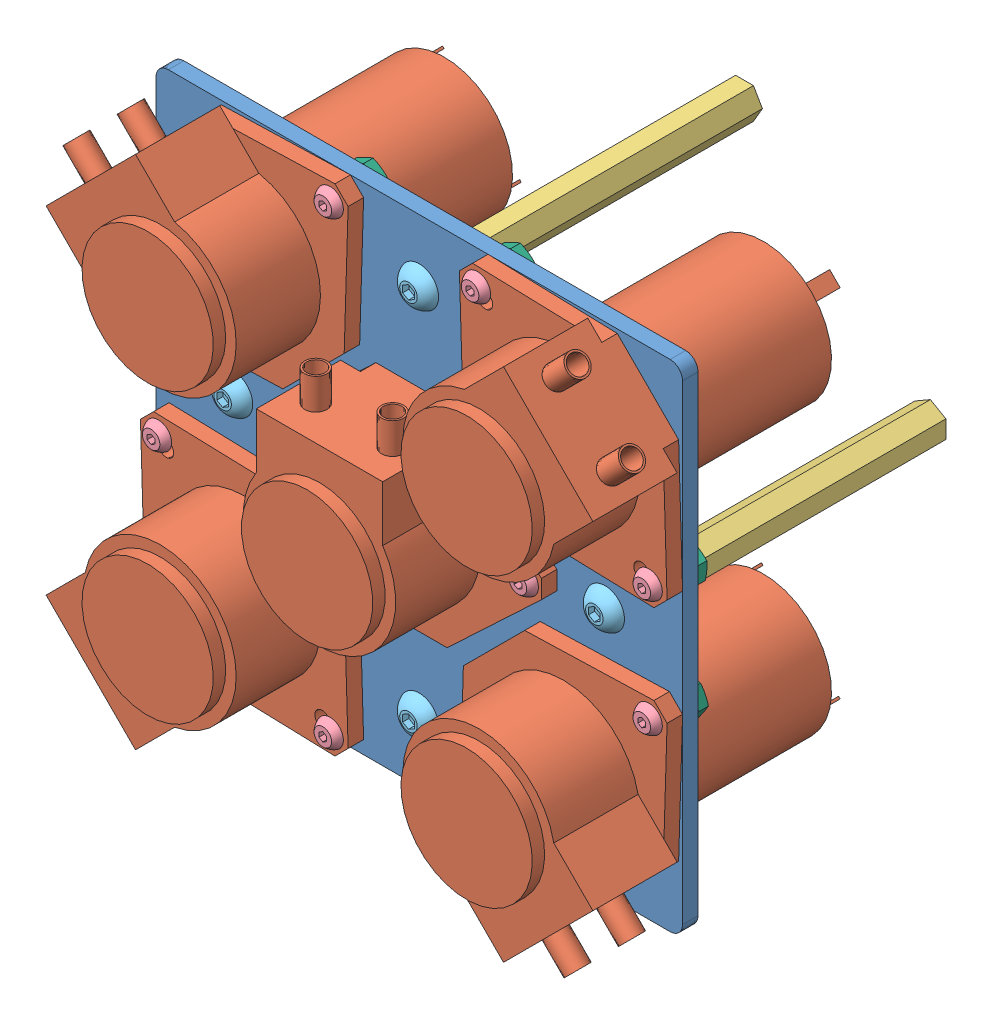
SolidWorks assembly pump_assembly, configuration Default. Lengths in mm.
Overall size (142.61 136.26 89.66).
34 component instances, 6 part files, 117 mates.
Components (placement in the parent):
- pump_mount02-1: pump_mount02 [Default] at (61.8269 35.897 80.89) size (107.95 101.6 3.17)
- water_pump-1: water_pump [Default] at (9.0816 76.7777 87.24) x (-0.707107 0.707107 0) z (-0.707107 -0.707107 0) size (56.39 67.44 46.48)
- water_pump-2: water_pump [Default] at (70.5317 64.9284 87.24) x (-0.707107 -0.707107 0) z (0.707107 -0.707107 0) size (56.39 67.44 46.48)
- water_pump-6: water_pump [Default] at (20.9309 131.8777 87.24) x (0.707107 0.707107 0) z (-0.707107 0.707107 0) size (56.39 67.44 46.48)
- water_pump-8: water_pump [Default] at (54.11 95.6216 87.24) x (1 0 0) z (0 1 0) size (56.39 67.44 46.48)
- 8-32x2p5_standoff_f-f-PFC-HRD-0008-2: 8-32x2p5_standoff_f-f-PFC-HRD-0008 [Default] at (90.9051 102.1286 17.39) x (0.238502 0.971142 0) z (0.971142 -0.238502 0) size (7.12 63.5 7.04)
- water_pump-7: water_pump [Default] at (82.381 120.0284 87.24) x (0.707107 -0.707107 0) z (0.707107 0.707107 0) size (56.39 67.44 46.48)
- 8-32x2p5_standoff_f-f-PFC-HRD-0008-3: 8-32x2p5_standoff_f-f-PFC-HRD-0008 [Default] at (49.9946 67.0664 17.39) x (-0.279022 0.960285 0) z (0.960285 0.279022 0) size (7.12 63.5 7.04)
- 8-32x2p5_standoff_f-f-PFC-HRD-0008-4: 8-32x2p5_standoff_f-f-PFC-HRD-0008 [Default] at (7.9417 106.3919 17.39) x (-0.721782 0.69212 0) z (0.69212 0.721782 0) size (7.12 63.5 7.04)
- 8-32x2p5_standoff_f-f-PFC-HRD-0008-5: 8-32x2p5_standoff_f-f-PFC-HRD-0008 [Default] at (42.0057 129.4293 80.89) x (-0.971142 -0.238502 0) z (0.238502 -0.971142 0) size (7.12 63.5 7.04)
- S-004-038-BTN-H-SS-001-440x3_8-button-head-screw-1: S-004-038-BTN-H-SS-001-440x3_8-button-head-screw [Default] at (96.0244 110.3185 87.24) x (1 0 0) z (0 -1 0) size (5.41 11.02 5.41)
- S-004-038-BTN-H-SS-001-440x3_8-button-head-screw-2: S-004-038-BTN-H-SS-001-440x3_8-button-head-screw [Default] at (30.6408 145.5211 87.24) x (1 0 0) z (0 -1 0) size (5.41 11.02 5.41)
- S-004-038-BTN-H-SS-001-440x3_8-button-head-screw-3: S-004-038-BTN-H-SS-001-440x3_8-button-head-screw [Default] at (60.8218 145.5211 87.24) x (1 0 0) z (0 -1 0) size (5.41 11.02 5.41)
- S-004-038-BTN-H-SS-001-440x3_8-button-head-screw-4: S-004-038-BTN-H-SS-001-440x3_8-button-head-screw [Default] at (-4.5618 110.3185 87.24) x (1 0 0) z (0 -1 0) size (5.41 11.02 5.41)
- S-004-038-BTN-H-SS-001-440x3_8-button-head-screw-9: S-004-038-BTN-H-SS-001-440x3_8-button-head-screw [Default] at (96.0244 86.4876 87.24) x (1 0 0) z (0 -1 0) size (5.41 11.02 5.41)
- S-004-038-BTN-H-SS-001-440x3_8-button-head-screw-10: S-004-038-BTN-H-SS-001-440x3_8-button-head-screw [Default] at (60.8218 51.2849 87.24) x (1 0 0) z (0 -1 0) size (5.41 11.02 5.41)
- S-004-038-BTN-H-SS-001-440x3_8-button-head-screw-11: S-004-038-BTN-H-SS-001-440x3_8-button-head-screw [Default] at (30.6408 51.2849 87.24) x (1 0 0) z (0 -1 0) size (5.41 11.02 5.41)
- S-004-038-BTN-H-SS-001-440x3_8-button-head-screw-12: S-004-038-BTN-H-SS-001-440x3_8-button-head-screw [Default] at (70.6233 98.403 87.24) x (1 0 0) z (0 -1 0) size (5.41 11.02 5.41)
- S-004-038-BTN-H-SS-001-440x3_8-button-head-screw-13: S-004-038-BTN-H-SS-001-440x3_8-button-head-screw [Default] at (20.8393 98.403 87.24) x (1 0 0) z (0 -1 0) size (5.41 11.02 5.41)
- S-004-038-BTN-H-SS-001-440x3_8-button-head-screw-14: S-004-038-BTN-H-SS-001-440x3_8-button-head-screw [Default] at (-4.5618 86.4876 87.24) x (1 0 0) z (0 -1 0) size (5.41 11.02 5.41)
- S-008-038-BTN-H-SS-001-832x3_8-button-head-screw-2: S-008-038-BTN-H-SS-001-832x3_8-button-head-screw [Default] at (45.7313 136.503 84.065) x (1 0 0) z (0 -1 0) size (7.92 11.73 7.92)
- S-008-038-BTN-H-SS-001-832x3_8-button-head-screw-3: S-008-038-BTN-H-SS-001-832x3_8-button-head-screw [Default] at (45.7313 60.303 84.065) x (1 0 0) z (0 -1 0) size (7.92 11.73 7.92)
- S-008-038-BTN-H-SS-001-832x3_8-button-head-screw-4: S-008-038-BTN-H-SS-001-832x3_8-button-head-screw [Default] at (83.8313 98.403 84.065) x (1 0 0) z (0 -1 0) size (7.92 11.73 7.92)
- S-008-038-BTN-H-SS-001-832x3_8-button-head-screw-5: S-008-038-BTN-H-SS-001-832x3_8-button-head-screw [Default] at (7.6313 98.403 84.065) x (1 0 0) z (0 -1 0) size (7.92 11.73 7.92)
- S-004-NUT-SS-001-440-SS-Nut-3_8thk-1: S-004-NUT-SS-001-440-SS-Nut-3_8thk [Default] at (96.0244 110.3185 78.5088) x (0.568823 0.82246 0) z (0.82246 -0.568823 0) size (6.35 2.38 7.33)
- S-004-NUT-SS-001-440-SS-Nut-3_8thk-2: S-004-NUT-SS-001-440-SS-Nut-3_8thk [Default] at (60.8218 145.5211 78.5088) x (0.568823 0.82246 0) z (0.82246 -0.568823 0) size (6.35 2.38 7.33)
- S-004-NUT-SS-001-440-SS-Nut-3_8thk-3: S-004-NUT-SS-001-440-SS-Nut-3_8thk [Default] at (-4.5618 110.3185 78.5088) x (-0.294621 -0.955614 0) z (-0.955614 0.294621 0) size (6.35 2.38 7.33)
- S-004-NUT-SS-001-440-SS-Nut-3_8thk-4: S-004-NUT-SS-001-440-SS-Nut-3_8thk [Default] at (30.6408 145.5211 78.5088) x (0.568823 0.82246 0) z (0.82246 -0.568823 0) size (6.35 2.38 7.33)
- S-004-NUT-SS-001-440-SS-Nut-3_8thk-5: S-004-NUT-SS-001-440-SS-Nut-3_8thk [Default] at (70.6233 98.403 78.5088) x (-0.294621 -0.955614 0) z (-0.955614 0.294621 0) size (6.35 2.38 7.33)
- S-004-NUT-SS-001-440-SS-Nut-3_8thk-6: S-004-NUT-SS-001-440-SS-Nut-3_8thk [Default] at (20.8393 98.403 78.5088) x (-0.294621 -0.955614 0) z (-0.955614 0.294621 0) size (6.35 2.38 7.33)
- S-004-NUT-SS-001-440-SS-Nut-3_8thk-7: S-004-NUT-SS-001-440-SS-Nut-3_8thk [Default] at (-4.5618 86.4876 78.5088) x (1 0 0) z (0 -1 0) size (6.35 2.38 7.33)
- S-004-NUT-SS-001-440-SS-Nut-3_8thk-8: S-004-NUT-SS-001-440-SS-Nut-3_8thk [Default] at (30.6408 51.2849 78.5088) x (1 0 0) z (0 -1 0) size (6.35 2.38 7.33)
- S-004-NUT-SS-001-440-SS-Nut-3_8thk-9: S-004-NUT-SS-001-440-SS-Nut-3_8thk [Default] at (60.8218 51.2849 78.5088) x (1 0 0) z (0 -1 0) size (6.35 2.38 7.33)
- S-004-NUT-SS-001-440-SS-Nut-3_8thk-10: S-004-NUT-SS-001-440-SS-Nut-3_8thk [Default] at (96.0244 86.4876 80.89) x (0.897016 0.441997 0) z (-0.441997 0.897016 0) size (6.35 2.38 7.33)
Mates (geometry in assembly coordinates):
- Coincident14: coincident: plane of pump_mount02-1 through (-8.2437 149.203 84.065) normal (0 1 0); line of water_pump-6 through (31.6286 149.203 84.065) axis (0 0 1)
- Coincident16: coincident: plane of pump_mount02-1 through (-8.2437 149.203 84.065) normal (-1 0 0); line of water_pump-6 through (-8.2437 109.3307 84.065) axis (0 0 1)
- Angle3: planar angle = 0.785398 rad anti-aligned: plane of water_pump-6 through (20.9421 107.4449 84.065) normal (0.707107 -0.707107 0); plane of pump_mount02-1 through (-8.2437 149.203 84.065) normal (0 1 0)
- Coincident20: coincident: plane of pump_mount02-1 through (-8.2437 149.203 84.065) normal (0 1 0); line of water_pump-7 through (59.8339 149.203 84.065) axis (0 0 1)
- Coincident21: coincident: plane of pump_mount02-1 through (99.7063 149.203 84.065) normal (1 0 0); line of water_pump-7 through (99.7063 109.3307 84.065) axis (0 0 1)
- Angle4: planar angle = 0.785398 rad anti-aligned: plane of water_pump-7 through (57.9481 120.0172 84.065) normal (-0.707107 -0.707107 0); plane of pump_mount02-1 through (99.7063 149.203 84.065) normal (1 0 0)
- Parallel6: parallel aligned: plane of water_pump-8 through (36.8413 78.337 84.065) normal (0 -1 0); plane of pump_mount02-1 through (-8.2437 47.603 84.065) normal (0 -1 0)
- Concentric1: concentric aligned: circle of pump_mount02-1; circle of water_pump-8
- Concentric2: concentric anti-aligned: circle of pump_mount02-1; circle of ?
- Coincident27: coincident anti-aligned: plane of pump_mount02-1 through (61.8269 35.897 80.89) normal (0 0 -1); plane of ? through (7.6313 103.9023 80.89) normal (0 0 1)
- Coincident28: coincident anti-aligned: plane of pump_mount02-1 through (61.8269 35.897 80.89) normal (0 0 -1); plane of ? through (3.7427 102.2916 80.89) normal (0 0 1)
- Concentric3: concentric aligned: circle of pump_mount02-1; circle of ?
- Concentric5: concentric aligned: circle of pump_mount02-1; circle of ?
- Coincident31: coincident anti-aligned: plane of pump_mount02-1 through (61.8269 35.897 80.89) normal (0 0 -1); plane of ? through (41.8427 140.3916 80.89) normal (0 0 1)
- Concentric8: concentric aligned: circle of pump_mount02-1; circle of ?
- Coincident34: coincident anti-aligned: plane of pump_mount02-1 through (61.8269 35.897 80.89) normal (0 0 -1); plane of ? through (85.2546 103.7149 80.89) normal (0 0 1)
- Coincident36: coincident anti-aligned: plane of pump_mount02-1 through (61.8269 35.897 80.89) normal (0 0 -1); plane of ? through (51.0432 61.7264 80.89) normal (0 0 1)
- Concentric9: concentric aligned: circle of pump_mount02-1; circle of ?
- Concentric11: concentric aligned: cylinder of pump_mount02-1 through (13.0395 68.8862 80.889) axis (0 0 1) radius 15.24; cylinder of water_pump-1 through (13.0395 68.8862 46.219) axis (0 0 1) radius 13.97
- Concentric12: concentric aligned: cylinder of pump_mount02-1 through (78.4231 68.8862 80.889) axis (0 0 1) radius 15.24; cylinder of water_pump-2 through (78.4231 68.8862 46.219) axis (0 0 1) radius 13.97
- Coincident38: coincident anti-aligned: plane of water_pump-7 through (82.381 120.0284 88.8275) normal (0 0 1); plane of ? through (60.8218 145.5211 88.8275) normal (0 0 -1)
- Concentric13: concentric anti-aligned: circle of pump_mount02-1; cylinder of ? through (60.8218 145.5211 91.6723) axis (0 0 -1) radius 2.3241
- Coincident44: coincident aligned: plane of ? through (47.1546 141.8149 80.89) normal (0.707107 0.707107 0); plane of ? through (85.2546 103.7149 80.89) normal (0.707107 0.707107 0)
- Parallel12: parallel aligned: plane of ? through (9.0546 103.7149 80.89) normal (0.707107 0.707107 0); plane of ? through (47.1546 141.8149 80.89) normal (0.707107 0.707107 0)
- Parallel13: parallel aligned: plane of ? through (87.7198 94.5145 80.89) normal (0.258819 -0.965926 0); plane of ? through (49.6198 56.4145 80.89) normal (0.258819 -0.965926 0)
- Concentric14: concentric anti-aligned: cylinder of pump_mount02-1 through (96.0244 110.3185 80.889) axis (0 0 1) radius 1.5875; cylinder of ? through (96.0244 110.3185 91.6723) axis (0 0 -1) radius 2.3241
- Coincident47: coincident anti-aligned: plane of water_pump-7 through (82.381 120.0284 88.8275) normal (0 0 1); plane of ? through (96.0244 110.3185 88.8275) normal (0 0 -1)
- Parallel14: parallel aligned: plane of water_pump-7 through (101.7717 132.9488 106.0995) normal (0.707107 -0.707107 0); plane of ? through (95.6685 111.6465 89.8864) normal (0.707107 -0.707107 0)
- Concentric15: concentric aligned: cylinder of pump_mount02-1 through (96.0244 86.4876 80.889) axis (0 0 1) radius 1.5875; cone of ? through (96.0244 86.4876 104.3723) axis (0 0 1)
- Concentric16: concentric anti-aligned: cylinder of pump_mount02-1 through (60.8218 51.2849 80.889) axis (0 0 1) radius 1.5875; cylinder of ? through (60.8218 51.2849 104.3723) axis (0 0 -1) radius 2.3241
- Parallel17: parallel aligned: plane of pump_mount02-1 through (-8.2437 149.203 85.6525) normal (0 1 0); plane of ? through (60.1344 144.3305 89.8864) normal (0 1 0)
- Concentric17: concentric: circle of pump_mount02-1; circle of ?
- Parallel18: parallel: plane of pump_mount02-1 through (99.7063 149.203 85.6525) normal (1 0 0); plane of ? through (98.4056 87.8624 98.3525) normal (1 0 0)
- Coincident58: coincident: plane of pump_mount02-1 through (61.8269 35.897 85.6525) normal (0 0 1); plane of ? through (96.0244 89.2372 85.6525) normal (0 0 -1)
- Coincident70: coincident anti-aligned: plane of pump_mount02-1 through (61.8269 35.897 80.89) normal (0 0 -1); plane of 8-32x2p5_standoff_f-f-PFC-HRD-0008-2 through (90.9051 102.1286 80.89) normal (0 0 1)
- Concentric24: concentric aligned: circle of pump_mount02-1; cylinder of 8-32x2p5_standoff_f-f-PFC-HRD-0008-2 through (83.8313 98.403 26.915) axis (0 0 -1) radius 1.7272
- Parallel22: parallel anti-aligned: plane of pump_mount02-1 through (99.7063 149.203 84.065) normal (1 0 0); plane of 8-32x2p5_standoff_f-f-PFC-HRD-0008-2 through (80.6563 100.2361 80.89) normal (-1 0 0)
- Coincident73: coincident anti-aligned: plane of pump_mount02-1 through (61.8269 35.897 80.89) normal (0 0 -1); plane of 8-32x2p5_standoff_f-f-PFC-HRD-0008-3 through (49.9946 67.0664 80.89) normal (0 0 1)
- Parallel24: parallel aligned: plane of pump_mount02-1 through (-8.2437 47.603 84.065) normal (0 -1 0); plane of 8-32x2p5_standoff_f-f-PFC-HRD-0008-3 through (43.8982 57.128 80.89) normal (0 -1 0)
- Coincident76: coincident anti-aligned: plane of pump_mount02-1 through (61.8269 35.897 80.89) normal (0 0 -1); plane of 8-32x2p5_standoff_f-f-PFC-HRD-0008-4 through (7.9417 106.3919 80.89) normal (0 0 1)
- Parallel25: parallel aligned: plane of pump_mount02-1 through (-8.2437 149.203 84.065) normal (-1 0 0); plane of 8-32x2p5_standoff_f-f-PFC-HRD-0008-4 through (4.4563 100.2361 80.89) normal (-1 0 0)
- Concentric27: concentric anti-aligned: circle of pump_mount02-1; cylinder of 8-32x2p5_standoff_f-f-PFC-HRD-0008-5 through (45.7313 136.503 71.365) axis (0 0 1) radius 1.7272
- Coincident78: coincident anti-aligned: plane of pump_mount02-1 through (61.8269 35.897 80.89) normal (0 0 -1); plane of 8-32x2p5_standoff_f-f-PFC-HRD-0008-5 through (42.0057 129.4293 80.89) normal (0 0 1)
- Parallel26: parallel aligned: plane of pump_mount02-1 through (-8.2437 149.203 84.065) normal (0 1 0); plane of 8-32x2p5_standoff_f-f-PFC-HRD-0008-5 through (43.8982 139.678 17.39) normal (0 1 0)
- Coincident80: coincident anti-aligned: plane of pump_mount02-1 through (61.8269 35.897 84.065) normal (0 0 1); plane of ? through (36.7986 46.6539 84.065) normal (0 0 -1)
- Concentric29: concentric aligned: circle of pump_mount02-1; circle of ?
- Parallel31: parallel aligned: plane of pump_mount02-1 through (-8.2437 47.603 84.065) normal (0 -1 0); plane of ? through (29.266 48.9037 103.115) normal (0 -1 0)
- Concentric30: concentric aligned: circle of pump_mount02-1; circle of 8-32x2p5_standoff_f-f-PFC-HRD-0008-3
- Concentric31: concentric anti-aligned: circle of pump_mount02-1; circle of ?
- Coincident88: coincident anti-aligned: plane of pump_mount02-1 through (61.8269 35.897 84.065) normal (0 0 1); plane of ? through (66.9796 55.916 84.065) normal (0 0 -1)
- Parallel34: parallel aligned: plane of pump_mount02-1 through (-8.2437 47.603 84.065) normal (0 -1 0); plane of ? through (62.1966 48.9037 84.065) normal (0 -1 0)
- Coincident90: coincident anti-aligned: plane of pump_mount02-1 through (61.8269 35.897 84.065) normal (0 0 1); plane of water_pump-6 through (20.9309 131.8777 84.065) normal (0 0 -1)
- Coincident91: coincident anti-aligned: plane of pump_mount02-1 through (61.8269 35.897 84.065) normal (0 0 1); plane of water_pump-7 through (82.381 120.0284 84.065) normal (0 0 -1)
- Coincident92: coincident anti-aligned: plane of pump_mount02-1 through (61.8269 35.897 84.065) normal (0 0 1); plane of water_pump-8 through (54.11 95.6216 84.065) normal (0 0 -1)
- Concentric32: concentric anti-aligned: cylinder of pump_mount02-1 through (60.8218 145.5211 80.889) axis (0 0 1) radius 1.5875; cylinder of S-004-038-BTN-H-SS-001-440x3_8-button-head-screw-3 through (60.8218 145.5211 77.715) axis (0 0 -1) radius 1.4224
- Coincident93: coincident anti-aligned: plane of water_pump-7 through (82.381 120.0284 87.24) normal (0 0 1); plane of S-004-038-BTN-H-SS-001-440x3_8-button-head-screw-3 through (59.3994 145.5211 87.24) normal (0 0 -1)
- Concentric33: concentric anti-aligned: cylinder of pump_mount02-1 through (96.0244 110.3185 80.889) axis (0 0 1) radius 1.5875; cylinder of S-004-038-BTN-H-SS-001-440x3_8-button-head-screw-1 through (96.0244 110.3185 77.715) axis (0 0 -1) radius 1.4224
- Coincident94: coincident anti-aligned: plane of water_pump-7 through (82.381 120.0284 87.24) normal (0 0 1); plane of S-004-038-BTN-H-SS-001-440x3_8-button-head-screw-1 through (94.602 110.3185 87.24) normal (0 0 -1)
- Concentric34: concentric anti-aligned: cylinder of pump_mount02-1 through (30.6408 145.5211 80.889) axis (0 0 1) radius 1.5875; cylinder of S-004-038-BTN-H-SS-001-440x3_8-button-head-screw-2 through (30.6408 145.5211 77.715) axis (0 0 -1) radius 1.4224
- Coincident95: coincident anti-aligned: plane of water_pump-6 through (20.9309 131.8777 87.24) normal (0 0 1); plane of S-004-038-BTN-H-SS-001-440x3_8-button-head-screw-2 through (29.2184 145.5211 87.24) normal (0 0 -1)
- Concentric35: concentric anti-aligned: cylinder of pump_mount02-1 through (-4.5618 110.3185 80.889) axis (0 0 1) radius 1.5875; cylinder of S-004-038-BTN-H-SS-001-440x3_8-button-head-screw-4 through (-4.5618 110.3185 77.715) axis (0 0 -1) radius 1.4224
- Coincident96: coincident anti-aligned: plane of water_pump-6 through (20.9309 131.8777 87.24) normal (0 0 1); plane of S-004-038-BTN-H-SS-001-440x3_8-button-head-screw-4 through (-5.9842 110.3185 87.24) normal (0 0 -1)
- Concentric36: concentric aligned: cylinder of pump_mount02-1 through (-4.5618 86.4876 80.889) axis (0 0 1) radius 1.5875; cylinder of ? through (-4.5618 86.4876 90.415) axis (0 0 1) radius 1.4224
- Coincident97: coincident anti-aligned: plane of pump_mount02-1 through (61.8269 35.897 80.89) normal (0 0 -1); plane of ? through (-3.2479 87.0324 80.89) normal (0 0 1)
- Concentric37: concentric aligned: cylinder of pump_mount02-1 through (30.6408 51.2849 80.889) axis (0 0 1) radius 1.5875; cylinder of ? through (30.6408 51.2849 90.415) axis (0 0 1) radius 1.4224
- Coincident98: coincident anti-aligned: plane of pump_mount02-1 through (61.8269 35.897 80.89) normal (0 0 -1); plane of ? through (31.9547 51.8298 80.89) normal (0 0 1)
- Concentric38: concentric aligned: cylinder of pump_mount02-1 through (60.8218 51.2849 80.889) axis (0 0 1) radius 1.5875; cylinder of ? through (60.8218 51.2849 90.415) axis (0 0 1) radius 1.4224
- Coincident99: coincident anti-aligned: plane of pump_mount02-1 through (61.8269 35.897 80.89) normal (0 0 -1); plane of ? through (62.1357 51.8298 80.89) normal (0 0 1)
- Concentric39: concentric aligned: cylinder of pump_mount02-1 through (96.0244 86.4876 80.889) axis (0 0 1) radius 1.5875; cylinder of ? through (96.0244 86.4876 90.415) axis (0 0 1) radius 1.4224
- Coincident100: coincident anti-aligned: plane of pump_mount02-1 through (61.8269 35.897 80.89) normal (0 0 -1); plane of ? through (97.3383 87.0324 80.89) normal (0 0 1)
- Coincident101: coincident anti-aligned: plane of water_pump-2 through (70.5317 64.9284 87.24) normal (0 0 1); plane of S-004-038-BTN-H-SS-001-440x3_8-button-head-screw-9 through (94.602 86.4876 87.24) normal (0 0 -1)
- Concentric41: concentric anti-aligned: cylinder of ? through (60.8218 51.2849 84.065) axis (0 0 1) radius 1.1303; cylinder of S-004-038-BTN-H-SS-001-440x3_8-button-head-screw-10 through (60.8218 51.2849 96.765) axis (0 0 -1) radius 1.4224
- Coincident102: coincident anti-aligned: plane of water_pump-2 through (70.5317 64.9284 87.24) normal (0 0 1); circle of S-004-038-BTN-H-SS-001-440x3_8-button-head-screw-10
- Concentric42: concentric aligned: cylinder of ? through (30.6408 51.2849 103.115) axis (0 0 -1) radius 1.1303; cylinder of S-004-038-BTN-H-SS-001-440x3_8-button-head-screw-11 through (30.6408 51.2849 96.765) axis (0 0 -1) radius 1.4224
- Coincident103: coincident anti-aligned: plane of water_pump-1 through (9.0816 76.7777 87.24) normal (0 0 1); plane of S-004-038-BTN-H-SS-001-440x3_8-button-head-screw-11 through (29.2184 51.2849 87.24) normal (0 0 -1)
- Coincident104: coincident anti-aligned: plane of water_pump-1 through (9.0816 76.7777 87.24) normal (0 0 1); plane of S-004-038-BTN-H-SS-001-440x3_8-button-head-screw-14 through (-5.9842 86.4876 87.24) normal (0 0 -1)
- Concentric43: concentric aligned: cylinder of ? through (-4.5618 86.4876 103.115) axis (0 0 -1) radius 1.1303; cylinder of S-004-038-BTN-H-SS-001-440x3_8-button-head-screw-14 through (-4.5618 86.4876 96.765) axis (0 0 -1) radius 1.4224
- Concentric44: concentric anti-aligned: cylinder of pump_mount02-1 through (20.8393 98.403 80.889) axis (0 0 1) radius 1.5875; cylinder of S-004-038-BTN-H-SS-001-440x3_8-button-head-screw-13 through (20.8393 98.403 77.715) axis (0 0 -1) radius 1.4224
- Coincident105: coincident anti-aligned: plane of water_pump-8 through (54.11 95.6216 87.24) normal (0 0 1); plane of S-004-038-BTN-H-SS-001-440x3_8-button-head-screw-13 through (19.4169 98.403 87.24) normal (0 0 -1)
- Concentric45: concentric anti-aligned: cylinder of pump_mount02-1 through (70.6233 98.403 80.889) axis (0 0 1) radius 1.5875; cylinder of S-004-038-BTN-H-SS-001-440x3_8-button-head-screw-12 through (70.6233 98.403 77.715) axis (0 0 -1) radius 1.4224
- Coincident106: coincident anti-aligned: plane of water_pump-8 through (54.11 95.6216 87.24) normal (0 0 1); plane of S-004-038-BTN-H-SS-001-440x3_8-button-head-screw-12 through (69.2009 98.403 87.24) normal (0 0 -1)
- Concentric46: concentric anti-aligned: cylinder of 8-32x2p5_standoff_f-f-PFC-HRD-0008-2 through (83.8313 98.403 71.365) axis (0 0 1) radius 1.7272; cylinder of S-008-038-BTN-H-SS-001-832x3_8-button-head-screw-4 through (83.8313 98.403 74.54) axis (0 0 -1) radius 2.0828
- Coincident107: coincident anti-aligned: plane of pump_mount02-1 through (61.8269 35.897 84.065) normal (0 0 1); plane of S-008-038-BTN-H-SS-001-832x3_8-button-head-screw-4 through (81.7485 98.403 84.065) normal (0 0 -1)
- Concentric47: concentric anti-aligned: cylinder of 8-32x2p5_standoff_f-f-PFC-HRD-0008-5 through (45.7313 136.503 71.365) axis (0 0 1) radius 1.7272; cylinder of S-008-038-BTN-H-SS-001-832x3_8-button-head-screw-2 through (45.7313 136.503 74.54) axis (0 0 -1) radius 2.0828
- Coincident108: coincident anti-aligned: plane of pump_mount02-1 through (61.8269 35.897 84.065) normal (0 0 1); plane of S-008-038-BTN-H-SS-001-832x3_8-button-head-screw-2 through (43.6485 136.503 84.065) normal (0 0 -1)
- Concentric48: concentric anti-aligned: cylinder of 8-32x2p5_standoff_f-f-PFC-HRD-0008-3 through (45.7313 60.303 71.365) axis (0 0 1) radius 1.7272; cylinder of S-008-038-BTN-H-SS-001-832x3_8-button-head-screw-3 through (45.7313 60.303 74.54) axis (0 0 -1) radius 2.0828
- Coincident109: coincident anti-aligned: plane of pump_mount02-1 through (61.8269 35.897 84.065) normal (0 0 1); plane of S-008-038-BTN-H-SS-001-832x3_8-button-head-screw-3 through (43.6485 60.303 84.065) normal (0 0 -1)
- Concentric50: concentric anti-aligned: cylinder of 8-32x2p5_standoff_f-f-PFC-HRD-0008-4 through (7.6313 98.403 71.365) axis (0 0 1) radius 1.7272; cylinder of S-008-038-BTN-H-SS-001-832x3_8-button-head-screw-5 through (7.6313 98.403 74.54) axis (0 0 -1) radius 2.0828
- Coincident110: coincident anti-aligned: plane of pump_mount02-1 through (61.8269 35.897 84.065) normal (0 0 1); plane of S-008-038-BTN-H-SS-001-832x3_8-button-head-screw-5 through (5.5485 98.403 84.065) normal (0 0 -1)
- Coincident111: coincident anti-aligned: plane of pump_mount02-1 through (61.8269 35.897 80.89) normal (0 0 -1); plane of S-004-NUT-SS-001-440-SS-Nut-3_8thk-1 through (96.0244 110.3185 80.89) normal (0 0 1)
- Concentric51: concentric aligned: cylinder of S-004-038-BTN-H-SS-001-440x3_8-button-head-screw-1 through (96.0244 110.3185 77.715) axis (0 0 -1) radius 1.4224; cylinder of S-004-NUT-SS-001-440-SS-Nut-3_8thk-1 through (96.0244 110.3185 80.89) axis (0 0 -1) radius 1.4351
- Concentric52: concentric aligned: cylinder of S-004-038-BTN-H-SS-001-440x3_8-button-head-screw-3 through (60.8218 145.5211 77.715) axis (0 0 -1) radius 1.4224; cylinder of S-004-NUT-SS-001-440-SS-Nut-3_8thk-2 through (60.8218 145.5211 80.89) axis (0 0 -1) radius 1.4351
- Coincident112: coincident anti-aligned: plane of pump_mount02-1 through (61.8269 35.897 80.89) normal (0 0 -1); plane of S-004-NUT-SS-001-440-SS-Nut-3_8thk-2 through (60.8218 145.5211 80.89) normal (0 0 1)
- Coincident113: coincident anti-aligned: plane of pump_mount02-1 through (61.8269 35.897 80.89) normal (0 0 -1); plane of S-004-NUT-SS-001-440-SS-Nut-3_8thk-4 through (30.6408 145.5211 80.89) normal (0 0 1)
- Concentric53: concentric aligned: cylinder of S-004-038-BTN-H-SS-001-440x3_8-button-head-screw-2 through (30.6408 145.5211 77.715) axis (0 0 -1) radius 1.4224; cylinder of S-004-NUT-SS-001-440-SS-Nut-3_8thk-4 through (30.6408 145.5211 80.89) axis (0 0 -1) radius 1.4351
- Coincident114: coincident anti-aligned: plane of pump_mount02-1 through (61.8269 35.897 80.89) normal (0 0 -1); plane of S-004-NUT-SS-001-440-SS-Nut-3_8thk-3 through (-4.5618 110.3185 80.89) normal (0 0 1)
- Concentric54: concentric aligned: cylinder of S-004-038-BTN-H-SS-001-440x3_8-button-head-screw-4 through (-4.5618 110.3185 77.715) axis (0 0 -1) radius 1.4224; cylinder of S-004-NUT-SS-001-440-SS-Nut-3_8thk-3 through (-4.5618 110.3185 80.89) axis (0 0 -1) radius 1.4351
- Coincident115: coincident anti-aligned: plane of pump_mount02-1 through (61.8269 35.897 80.89) normal (0 0 -1); plane of S-004-NUT-SS-001-440-SS-Nut-3_8thk-5 through (70.6233 98.403 80.89) normal (0 0 1)
- Concentric55: concentric aligned: cylinder of S-004-038-BTN-H-SS-001-440x3_8-button-head-screw-12 through (70.6233 98.403 77.715) axis (0 0 -1) radius 1.4224; cylinder of S-004-NUT-SS-001-440-SS-Nut-3_8thk-5 through (70.6233 98.403 80.89) axis (0 0 -1) radius 1.4351
- Coincident116: coincident anti-aligned: plane of pump_mount02-1 through (61.8269 35.897 80.89) normal (0 0 -1); plane of S-004-NUT-SS-001-440-SS-Nut-3_8thk-6 through (20.8393 98.403 80.89) normal (0 0 1)
- Concentric56: concentric aligned: cylinder of S-004-038-BTN-H-SS-001-440x3_8-button-head-screw-13 through (20.8393 98.403 77.715) axis (0 0 -1) radius 1.4224; cylinder of S-004-NUT-SS-001-440-SS-Nut-3_8thk-6 through (20.8393 98.403 80.89) axis (0 0 -1) radius 1.4351
- Coincident117: coincident anti-aligned: plane of pump_mount02-1 through (61.8269 35.897 84.065) normal (0 0 1); plane of water_pump-1 through (9.0816 76.7777 84.065) normal (0 0 -1)
- Concentric57: concentric aligned: cylinder of pump_mount02-1 through (-4.5618 86.4876 80.889) axis (0 0 1) radius 1.5875; cylinder of water_pump-1 through (-4.5618 86.4876 39.614) axis (0 0 1) radius 1.524
- Concentric58: concentric anti-aligned: cylinder of water_pump-1 through (-4.5618 86.4876 39.614) axis (0 0 1) radius 1.524; cylinder of S-004-038-BTN-H-SS-001-440x3_8-button-head-screw-14 through (-4.5618 86.4876 77.715) axis (0 0 -1) radius 1.4224
- Concentric59: concentric anti-aligned: cylinder of water_pump-1 through (30.6408 51.2849 39.614) axis (0 0 1) radius 1.524; cylinder of S-004-038-BTN-H-SS-001-440x3_8-button-head-screw-11 through (30.6408 51.2849 77.715) axis (0 0 -1) radius 1.4224
- Coincident118: coincident anti-aligned: plane of pump_mount02-1 through (61.8269 35.897 84.065) normal (0 0 1); plane of water_pump-2 through (70.5317 64.9284 84.065) normal (0 0 -1)
- Concentric60: concentric anti-aligned: cylinder of water_pump-2 through (60.8218 51.2849 39.614) axis (0 0 1) radius 1.524; cylinder of S-004-038-BTN-H-SS-001-440x3_8-button-head-screw-10 through (60.8218 51.2849 77.715) axis (0 0 -1) radius 1.4224
- Concentric61: concentric aligned: cylinder of pump_mount02-1 through (60.8218 51.2849 80.889) axis (0 0 1) radius 1.5875; cylinder of water_pump-2 through (60.8218 51.2849 39.614) axis (0 0 1) radius 1.524
- Concentric62: concentric anti-aligned: cylinder of water_pump-2 through (96.0244 86.4876 39.614) axis (0 0 1) radius 1.524; cylinder of S-004-038-BTN-H-SS-001-440x3_8-button-head-screw-9 through (96.0244 86.4876 77.715) axis (0 0 -1) radius 1.4224
- Coincident119: coincident anti-aligned: plane of pump_mount02-1 through (61.8269 35.897 80.89) normal (0 0 -1); plane of S-004-NUT-SS-001-440-SS-Nut-3_8thk-7 through (-4.5618 86.4876 80.89) normal (0 0 1)
- Concentric63: concentric aligned: cylinder of S-004-038-BTN-H-SS-001-440x3_8-button-head-screw-14 through (-4.5618 86.4876 77.715) axis (0 0 -1) radius 1.4224; cylinder of S-004-NUT-SS-001-440-SS-Nut-3_8thk-7 through (-4.5618 86.4876 80.89) axis (0 0 -1) radius 1.4351
- Coincident120: coincident anti-aligned: plane of pump_mount02-1 through (61.8269 35.897 80.89) normal (0 0 -1); plane of S-004-NUT-SS-001-440-SS-Nut-3_8thk-8 through (30.6408 51.2849 80.89) normal (0 0 1)
- Concentric64: concentric aligned: cylinder of S-004-038-BTN-H-SS-001-440x3_8-button-head-screw-11 through (30.6408 51.2849 77.715) axis (0 0 -1) radius 1.4224; cylinder of S-004-NUT-SS-001-440-SS-Nut-3_8thk-8 through (30.6408 51.2849 80.89) axis (0 0 -1) radius 1.4351
- Coincident121: coincident anti-aligned: plane of pump_mount02-1 through (61.8269 35.897 80.89) normal (0 0 -1); plane of S-004-NUT-SS-001-440-SS-Nut-3_8thk-9 through (60.8218 51.2849 80.89) normal (0 0 1)
- Concentric65: concentric aligned: cylinder of S-004-038-BTN-H-SS-001-440x3_8-button-head-screw-10 through (60.8218 51.2849 77.715) axis (0 0 -1) radius 1.4224; cylinder of S-004-NUT-SS-001-440-SS-Nut-3_8thk-9 through (60.8218 51.2849 80.89) axis (0 0 -1) radius 1.4351
- Concentric66: concentric anti-aligned: cylinder of S-004-038-BTN-H-SS-001-440x3_8-button-head-screw-9 through (96.0244 86.4876 77.715) axis (0 0 -1) radius 1.4224; cylinder of S-004-NUT-SS-001-440-SS-Nut-3_8thk-10 through (96.0244 86.4876 78.5088) axis (0 0 1) radius 1.4351
- Coincident122: coincident anti-aligned: plane of pump_mount02-1 through (61.8269 35.897 80.89) normal (0 0 -1); plane of S-004-NUT-SS-001-440-SS-Nut-3_8thk-10 through (96.0244 86.4876 80.89) normal (0 0 1)
